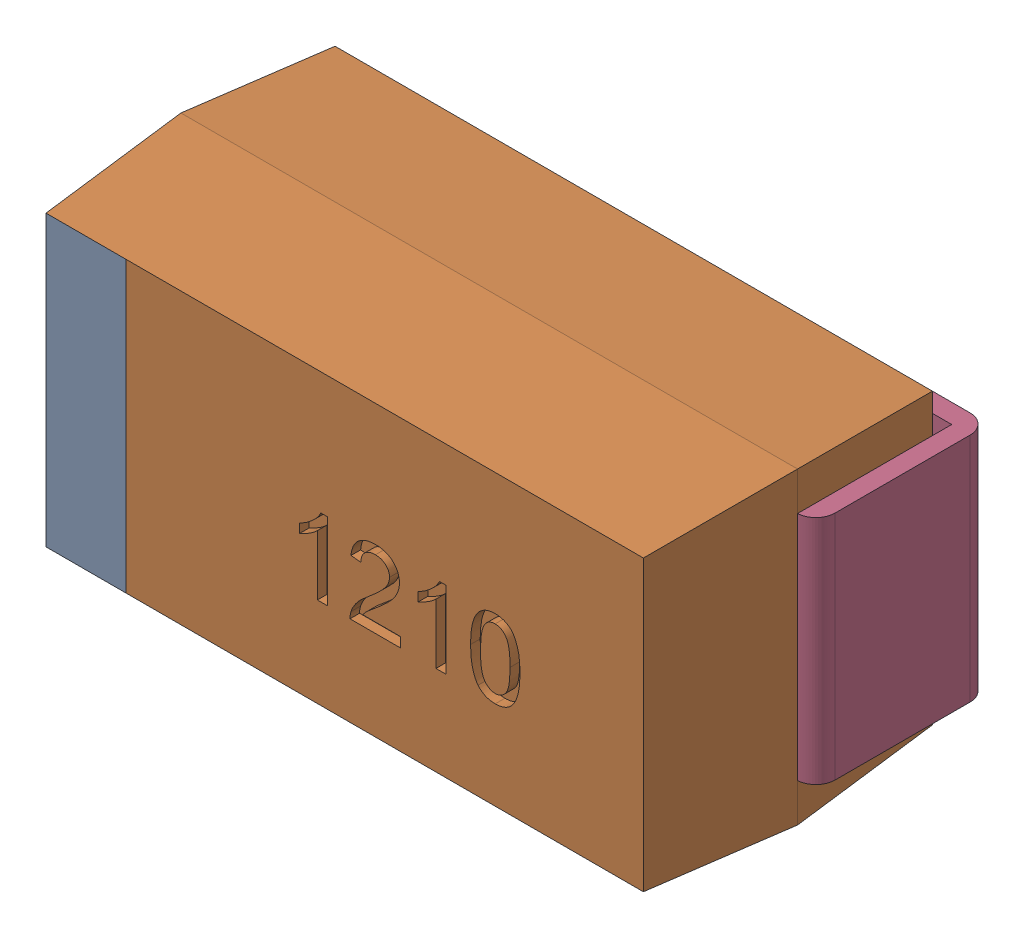
SolidWorks assembly C17, configuration Default. Lengths in mm.
Overall size (3.39 1.6 1.65).
4 component instances, 2 part files, 0 mates.
Components (placement in the parent):
- User_Library-Tantalum_Capacitor_Case_A-1: User_Library-Tantalum_Capacitor_Case_A [Default] at (49.4191 13.5301 0.05) x (1 0 0) z (0 0 1) size (3.39 1.6 1.65)
  - User_Library-Tantalum_Capacitor_Case_A_Tantalum_case_A_part1-1: User_Library-Tantalum_Capacitor_Case_A_Tantalum_case_A_part1 [Default] at (-1.5973 -0.8 0.1) size (3.2 1.6 1.6)
  - User_Library-Tantalum_Capacitor_Case_A_Tantalum_case_A_part2-1: User_Library-Tantalum_Capacitor_Case_A_Tantalum_case_A_part2 [Default] at (-0.8925 -0.6 0.05) x (-1 0 0) z (0 0 -1) size (0.8 1.2 0.9)
  - User_Library-Tantalum_Capacitor_Case_A_Tantalum_case_A_part2-2: User_Library-Tantalum_Capacitor_Case_A_Tantalum_case_A_part2 [Default] at (0.8979 0.6 0.05) x (1 0 0) z (0 0 -1) size (0.8 1.2 0.9)
